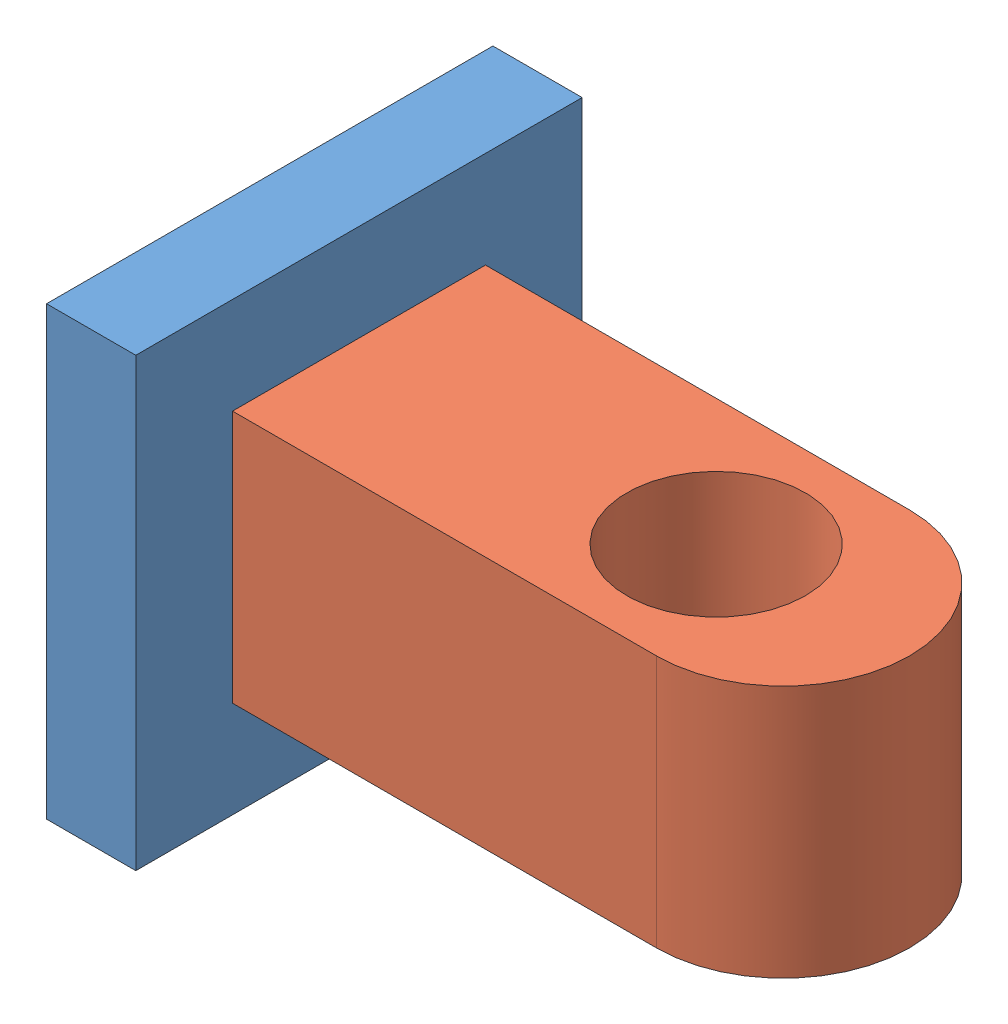
SolidWorks assembly połączenie sworzeniowe, configuration Domyślna. Lengths in mm.
Overall size (86 60 60).
2 component instances, 2 part files, 1 mates.
Components (placement in the parent):
- sworzeniowe podkładka-1: sworzeniowe podkładka [Domyślna] at (-11.2967 -40.4478 60) size (12 60 60)
- Sworzeniowe-1: Sworzeniowe [Domyślna<Obrobiona>] at (15.7014 -10.1965 79.4845) x (1 0 0) z (0 -1 0) size (74 34 34)
Mates (geometry in assembly coordinates):
- Centrum profilów1: profile center anti-aligned: plane of sworzeniowe podkładka-1 through (-27.3278 19.8035 120) normal (1 0 0); plane of Sworzeniowe-1 through (-27.3278 6.8035 79.4845) normal (-1 0 0)
